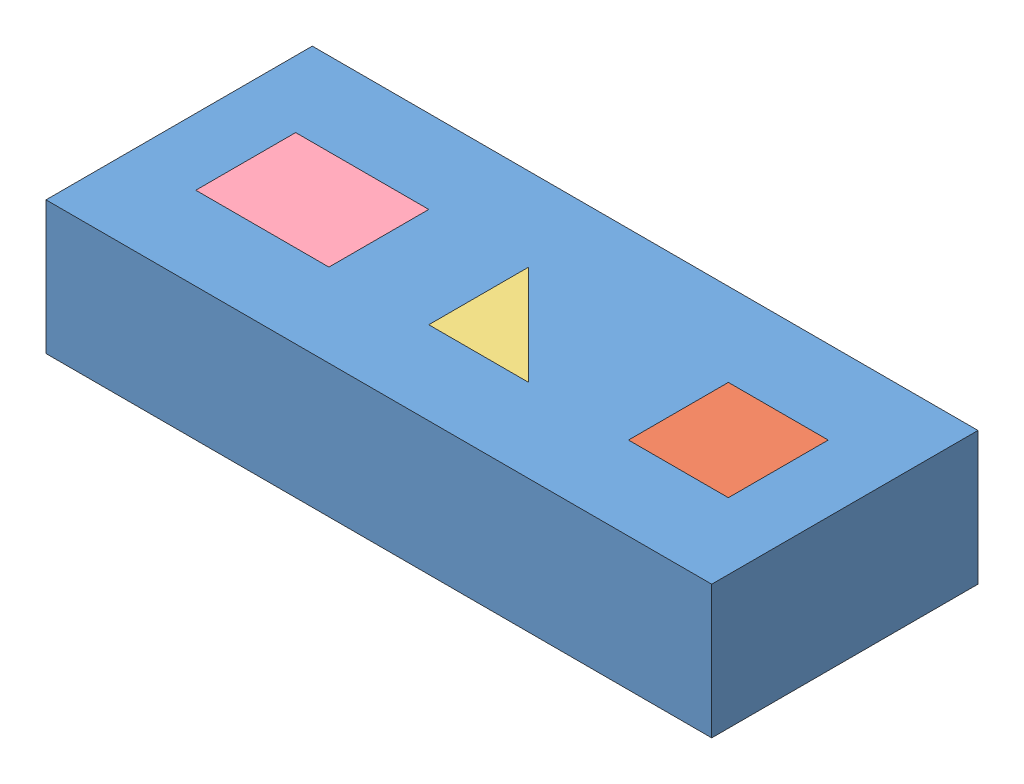
SolidWorks assembly Assem1, configuration Default. Lengths in mm.
Overall size (127 25.4 50.8).
4 component instances, 4 part files, 8 mates.
Components (placement in the parent):
- Block_Coinc_parallel_prepend_2013 (1)-1: Block_Coinc_parallel_prepend_2013 (1) [Default] at (-23.9353 52.4261 127.8019) size (127 25.4 50.8)
- Square_2013-1: Square_2013 [Default] at (71.3147 52.4261 111.9269) size (19.05 25.4 19.05)
- Traingle_2013-1: Traingle_2013 [Default] at (33.2147 52.4261 111.9269) size (19.05 25.4 19.05)
- rectangle_1_2013-2: rectangle_1_2013 [Default] at (-11.2353 52.4261 111.9269) size (25.4 25.4 19.05)
Mates (geometry in assembly coordinates):
- Coincident13: coincident aligned: plane of Block_Coinc_parallel_prepend_2013 (1)-1 through (-23.9353 77.8261 127.8019) normal (0 1 0); plane of rectangle_1_2013-2 through (-11.2353 77.8261 111.9269) normal (0 1 0)
- Coincident14: coincident aligned: line of Block_Coinc_parallel_prepend_2013 (1)-1 through (14.1647 77.8261 92.8769) axis (-1 0 0); line of rectangle_1_2013-2 through (14.1647 77.8261 92.8769) axis (-1 0 0)
- Coincident16: coincident aligned: line of Block_Coinc_parallel_prepend_2013 (1)-1 through (-11.2353 77.8261 92.8769) axis (0 0 1); line of rectangle_1_2013-2 through (-11.2353 77.8261 92.8769) axis (0 0 1)
- Coincident18: coincident aligned: plane of Block_Coinc_parallel_prepend_2013 (1)-1 through (-23.9353 77.8261 127.8019) normal (0 1 0); plane of Traingle_2013-1 through (33.2147 77.8261 111.9269) normal (0 1 0)
- Coincident19: coincident aligned: line of Block_Coinc_parallel_prepend_2013 (1)-1 through (33.2147 77.8261 92.8769) axis (0 0 1); line of Traingle_2013-1 through (33.2147 77.8261 92.8769) axis (0 0 1)
- Coincident20: coincident aligned: line of Block_Coinc_parallel_prepend_2013 (1)-1 through (33.2147 77.8261 111.9269) axis (1 0 0); line of Traingle_2013-1 through (33.2147 77.8261 111.9269) axis (1 0 0)
- Coincident22: coincident: line of Block_Coinc_parallel_prepend_2013 (1)-1 through (90.3647 77.8261 92.8769) axis (-1 0 0); line of Square_2013-1 through (90.3647 77.8261 92.8769) axis (-1 0 0)
- Coincident23: coincident aligned: line of Block_Coinc_parallel_prepend_2013 (1)-1 through (71.3147 77.8261 92.8769) axis (0 0 1); line of Square_2013-1 through (71.3147 77.8261 92.8769) axis (0 0 1)
